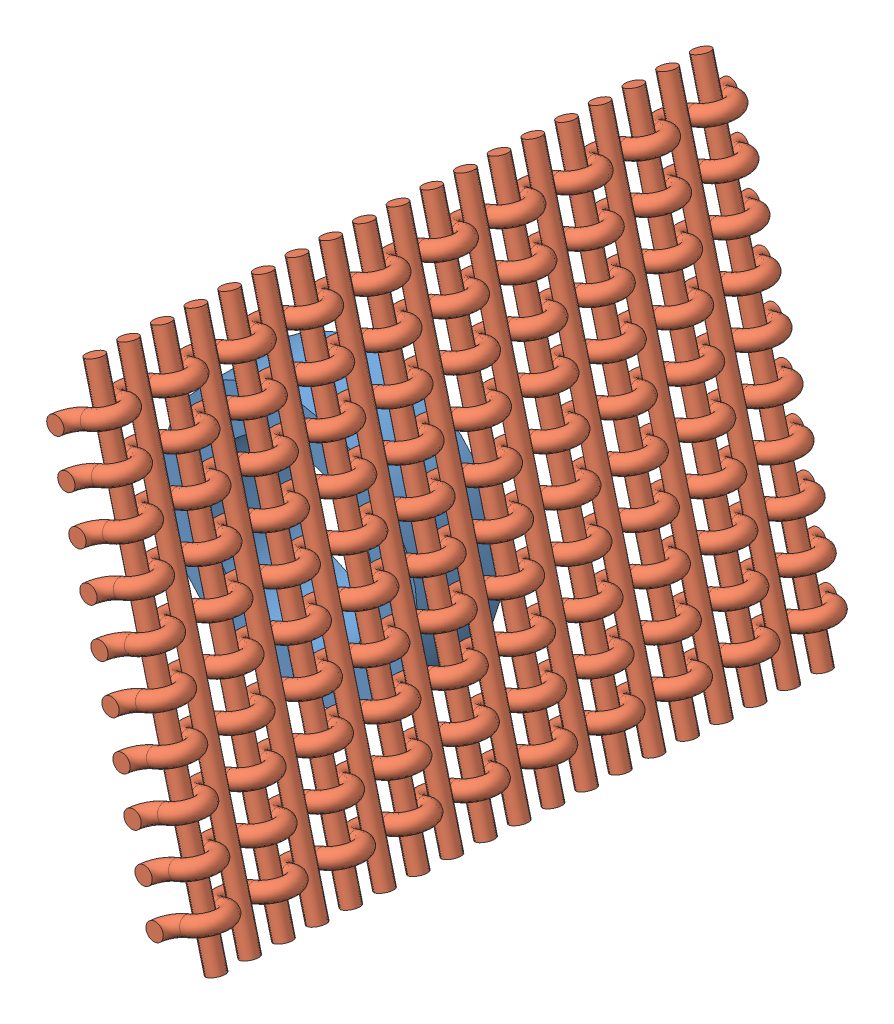
SolidWorks assembly gak, configuration По умолчанию. Lengths in mm.
Overall size (43.08 59.9 83.73).
2 component instances, 2 part files, 1 mates.
Components (placement in the parent):
- гак-1: гак [По умолчанию] at (56.2769 10.4421 14.8846) size (30 30 10)
- резина-1: резина [По умолчанию] at (25.1799 53.8143 57.2782) x (0.326423 -0.942752 0.068313) z (0.011703 0.076297 0.997016) size (55 6 80)
Mates (geometry in assembly coordinates):
- Касательность4: tangent: cylinder of гак-1 through (16.2769 20.4421 24.8846) axis (0 0 -1) radius 15; torus of резина-1
